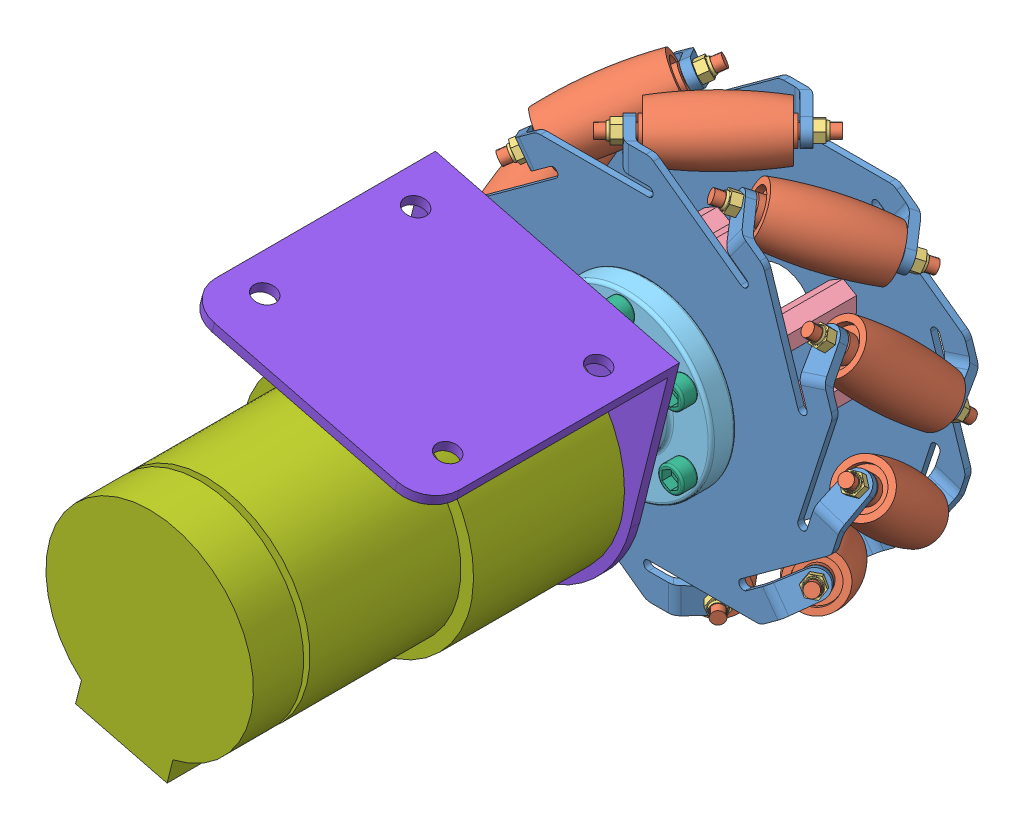
SolidWorks assembly 右前轮, configuration 默认. Lengths in mm.
Overall size (73.24 70.84 106.5).
61 component instances, 8 part files, 9 mates.
Components (placement in the parent):
- 麦克纳姆轮装配-1: 麦克纳姆轮装配 [默认] at (2.8929 6.1368 18.4053) size (73.24 68.83 28.84)
  - 麦克纳姆轮-1: 麦克纳姆轮 [默认] at (0.4661 -9.5096 64.9154) size (62.94 61.45 5.94)
  - 麦克纳姆轮-2: 麦克纳姆轮 [默认] at (0.4661 -9.5096 44.7758) x (-1 0 0) z (0 0 -1) size (62.94 61.45 5.94)
  - 辊子-3: 辊子 [默认] at (-10.8507 19.0898 66.1624) x (0.707107 0 -0.707107) z (0.707107 0 0.707107) size (28 9.23 9.23)
  - 辊子-4: 辊子 [默认] at (-25.5101 6.9683 66.1753) x (0.572061 0.415627 -0.707107) z (-0.42304 -0.589076 -0.688496) size (28 9.23 9.23)
  - 辊子-5: 辊子 [默认] at (-30.2306 -11.4349 66.1624) x (0.218508 0.672499 -0.707107) z (0.707107 0.390255 0.589662) size (28 9.23 9.23)
  - 辊子-6: 辊子 [默认] at (-23.2364 -29.1103 66.1624) x (-0.218508 0.672499 -0.707107) z (0.108472 0.736865 0.667281) size (28 9.23 9.23)
  - 辊子-7: 辊子 [默认] at (-25.5101 -25.9875 43.5158) x (0.572061 -0.415627 0.707107) z (-0.707107 0.186947 0.681946) size (28 9.23 9.23)
  - 辊子-8: 辊子 [默认] at (-10.8636 -38.109 43.5158) x (0.707107 0 0.707107) z (0.12537 -0.984157 -0.12537) size (28 9.23 9.23)
  - 辊子-9: 辊子 [默认] at (8.1104 -39.3064 43.5158) x (0.572061 0.415627 0.707107) z (-0.707107 -0.186947 0.681946) size (28 9.23 9.23)
  - 辊子-10: 辊子 [默认] at (24.1647 -29.1225 43.5158) x (0.218508 0.672499 0.707107) z (-0.707107 -0.390255 0.589662) size (28 9.23 9.23)
  - 辊子-11: 辊子 [默认] at (8.1209 20.2797 66.1624) x (0.572061 -0.415627 -0.707107) z (0.707107 -0.186947 0.681946) size (28 9.23 9.23)
  - 辊子-12: 辊子 [默认] at (31.1668 -11.4472 43.5158) x (-0.218508 0.672499 0.707107) z (-0.805898 -0.532961 0.25784) size (28 9.23 9.23)
  - M2【螺母】-1: M2【螺母】 [默认] at (-9.3907 18.6798 46.2506) x (0.808299 -0.139279 0.572061) z (-0.572061 -0.415627 0.707107) size (2.79 3.22 1.95)
  - M2【螺母】-2: M2【螺母】 [默认] at (9.0611 19.0898 46.2506) x (0.707107 0 0.707107) z (-0.707107 0 0.707107) size (2.79 3.22 1.95)
  - M2【螺母】-3: M2【螺母】 [默认] at (24.2299 8.5758 46.2506) x (0.808299 0.139279 0.572061) z (-0.572061 0.415627 0.707107) size (2.79 3.22 1.95)
  - M2【螺母】-4: M2【螺母】 [默认] at (30.3217 -8.8462 46.2506) x (0.972031 0.086079 0.218508) z (-0.218508 0.672499 0.707107) size (2.79 3.22 1.95)
  - M2【螺母】-5: M2【螺母】 [默认] at (25.0098 -26.5216 46.2506) x (0.972031 -0.086079 -0.218508) z (0.218508 0.672499 0.707107) size (2.79 3.22 1.95)
  - M2【螺母】-6: M2【螺母】 [默认] at (10.323 -37.699 46.2506) x (0.808299 -0.139279 -0.572061) z (0.572061 0.415627 0.707107) size (2.79 3.22 1.95)
  - M2【螺母】-7: M2【螺母】 [默认] at (-8.1288 -38.109 46.2506) x (0.707107 0 -0.707107) z (0.707107 0 0.707107) size (2.79 3.22 1.95)
  - M2【螺母】-8: M2【螺母】 [默认] at (-23.2976 -27.595 46.2506) x (0.808299 0.139279 -0.572061) z (0.572061 -0.415627 0.707107) size (2.79 3.22 1.95)
  - M2【螺母】-9: M2【螺母】 [默认] at (-29.3895 -10.173 46.2506) x (0.972031 0.086079 -0.218508) z (0.218508 -0.672499 0.707107) size (2.79 3.22 1.95)
  - M2【螺母】-10: M2【螺母】 [默认] at (-24.0775 7.5024 46.2506) x (0.972031 -0.086079 0.218508) z (-0.218508 -0.672499 0.707107) size (2.79 3.22 1.95)
  - M2【螺母】-11: M2【螺母】 [默认] at (30.3217 -10.173 63.4405) x (-0.703826 -0.39331 0.591554) z (-0.218508 -0.672499 -0.707107) size (2.79 3.22 1.95)
  - M2【螺母】-13: M2【螺母】 [默认] at (25.0098 7.5024 63.4405) x (0.835211 -0.245852 0.491913) z (0.218508 -0.672499 -0.707107) size (2.79 3.22 1.95)
  - M2【螺母】-14: M2【螺母】 [默认] at (10.323 18.6798 63.4405) x (0.731274 -0.131986 0.669192) z (0.572061 -0.415627 -0.707107) size (2.79 3.22 1.95)
  - M2【螺母】-15: M2【螺母】 [默认] at (-8.1288 19.0898 63.4405) x (0.610509 -0.504536 0.610509) z (0.707107 0 -0.707107) size (2.79 3.22 1.95)
  - M2【螺母】-16: M2【螺母】 [默认] at (-23.2976 8.5758 63.4405) x (0.785961 -0.524301 0.327679) z (0.572061 0.415627 -0.707107) size (2.79 3.22 1.95)
  - M2【螺母】-17: M2【螺母】 [默认] at (-29.3895 -8.8462 63.4405) x (0.874876 -0.455982 -0.163313) z (0.218508 0.672499 -0.707107) size (2.79 3.22 1.95)
  - M2【螺母】-18: M2【螺母】 [默认] at (-24.0775 -26.5216 63.4405) x (0.829372 -0.253837 -0.497703) z (-0.218508 0.672499 -0.707107) size (2.79 3.22 1.95)
  - M2【螺母】-19: M2【螺母】 [默认] at (-9.3907 -37.699 63.4405) x (0.565426 -0.424684 -0.707062) z (-0.572061 0.415627 -0.707107) size (2.79 3.22 1.95)
  - M2【螺母】-20: M2【螺母】 [默认] at (9.0611 -38.109 63.4405) x (0.556393 -0.617133 -0.556393) z (-0.707107 0 -0.707107) size (2.79 3.22 1.95)
  - M2【螺母】-21: M2【螺母】 [默认] at (24.2299 -27.595 63.4405) x (0.779137 -0.544759 -0.310134) z (-0.572061 -0.415627 -0.707107) size (2.79 3.22 1.95)
  - 20mm长-M3【六角铜柱】-1: 20mm长-M3【六角铜柱】 [默认] at (-9.4932 -3.7596 44.9154) size (4.27 4.93 20)
  - 20mm长-M3【六角铜柱】-2: 20mm长-M3【六角铜柱】 [默认] at (-9.4932 -15.2596 44.9154) x (0.5 0.866025 0) z (0 0 1) size (4.27 4.93 20)
  - 20mm长-M3【六角铜柱】-3: 20mm长-M3【六角铜柱】 [默认] at (0.4661 -21.0096 44.9154) x (-0.5 0.866025 0) z (0 0 1) size (4.27 4.93 20)
  - 20mm长-M3【六角铜柱】-4: 20mm长-M3【六角铜柱】 [默认] at (10.4254 -15.2596 44.9154) x (-1 0 0) z (0 0 1) size (4.27 4.93 20)
  - 20mm长-M3【六角铜柱】-5: 20mm长-M3【六角铜柱】 [默认] at (10.4254 -3.7596 44.9154) x (-0.5 -0.866025 0) z (0 0 1) size (4.27 4.93 20)
  - 20mm长-M3【六角铜柱】-6: 20mm长-M3【六角铜柱】 [默认] at (0.4661 1.9904 44.9154) x (0.5 -0.866025 0) z (0 0 1) size (4.27 4.93 20)
- 法兰联轴器-1: 法兰联轴器 [默认] at (3.3591 -3.3728 84.3207) size (28 28 16)
- M3-8【内六角螺丝】-1: M3-8【内六角螺丝】 [默认] at (3.3591 -14.8728 80.3207) size (4 4 10.5)
- M3-8【内六角螺丝】-2: M3-8【内六角螺丝】 [默认] at (13.3184 -9.1228 80.3207) x (0.5 0.866025 0) z (0 0 1) size (4 4 10.5)
- M3-8【内六角螺丝】-3: M3-8【内六角螺丝】 [默认] at (13.3184 2.3772 80.3207) x (-0.5 0.866025 0) z (0 0 1) size (4 4 10.5)
- M3-8【内六角螺丝】-4: M3-8【内六角螺丝】 [默认] at (3.3591 8.1272 80.3207) x (-1 0 0) z (0 0 1) size (4 4 10.5)
- M3-8【内六角螺丝】-5: M3-8【内六角螺丝】 [默认] at (-6.6002 2.3772 80.3207) x (-0.5 -0.866025 0) z (0 0 1) size (4 4 10.5)
- M3-8【内六角螺丝】-6: M3-8【内六角螺丝】 [默认] at (-6.6002 -9.1228 80.3207) x (0.5 -0.866025 0) z (0 0 1) size (4 4 10.5)
- M3-8【内六角螺丝】-7: M3-8【内六角螺丝】 [默认] at (3.3591 -14.8728 70.1811) x (1 0 0) z (0 0 -1) size (4 4 10.5)
- M3-8【内六角螺丝】-8: M3-8【内六角螺丝】 [默认] at (-6.6002 -9.1228 70.1811) x (0.5 -0.866025 0) z (0 0 -1) size (4 4 10.5)
- M3-8【内六角螺丝】-9: M3-8【内六角螺丝】 [默认] at (-6.6002 2.3772 70.1811) x (-0.5 -0.866025 0) z (0 0 -1) size (4 4 10.5)
- M3-8【内六角螺丝】-10: M3-8【内六角螺丝】 [默认] at (3.3591 8.1272 70.1811) x (-1 0 0) z (0 0 -1) size (4 4 10.5)
- M3-8【内六角螺丝】-11: M3-8【内六角螺丝】 [默认] at (13.3184 2.3772 70.1811) x (-0.5 0.866025 0) z (0 0 -1) size (4 4 10.5)
- M3-8【内六角螺丝】-12: M3-8【内六角螺丝】 [默认] at (13.3184 -9.1228 70.1811) x (0.5 0.866025 0) z (0 0 -1) size (4 4 10.5)
- 电机总装-1: 电机总装 [默认] at (86.3591 63.7866 -71.3943) x (0.969845 -0.243724 0) z (0 0 1) size (40 46 75)
  - 减速比1：10【码盘减速电机】-1: 减速比1：10【码盘减速电机】 [默认] at (-64.1287 -78.3632 203.7151) x (1 0 0) z (0 0 -1) size (37 37 75)
  - 电机支架-2: 电机支架 [默认] at (-64.1287 -78.3632 179.7151) x (1 0 0) z (0 0 -1) size (40 46 40)
  - M3-8【内六角螺丝】-13: M3-8【内六角螺丝】 [默认] at (-56.3787 -64.9398 186.2151) x (-1 0 0) z (0 0 -1) size (4 4 10.5)
  - M3-8【内六角螺丝】-14: M3-8【内六角螺丝】 [默认] at (-71.8787 -64.9398 186.2151) x (-0.5 -0.866025 0) z (0 0 -1) size (4 4 10.5)
  - M3-8【内六角螺丝】-15: M3-8【内六角螺丝】 [默认] at (-79.6287 -78.3632 186.2151) x (0.5 -0.866025 0) z (0 0 -1) size (4 4 10.5)
  - M3-8【内六角螺丝】-16: M3-8【内六角螺丝】 [默认] at (-71.8787 -91.7866 186.2151) x (1 0 0) z (0 0 -1) size (4 4 10.5)
  - M3-8【内六角螺丝】-17: M3-8【内六角螺丝】 [默认] at (-56.3787 -91.7866 186.2151) x (0.5 0.866025 0) z (0 0 -1) size (4 4 10.5)
  - M3-8【内六角螺丝】-18: M3-8【内六角螺丝】 [默认] at (-48.6287 -78.3632 186.2151) x (-0.5 0.866025 0) z (0 0 -1) size (4 4 10.5)
Mates (geometry in assembly coordinates):
- 同心1: concentric: cylinder of assembly; cylinder of assembly; cylinder of 麦克纳姆轮装配-1/麦克纳姆轮-1 through (3.3591 -3.3728 83.3207) axis (0 0 1) radius 5; cylinder of 法兰联轴器-1 through (3.3591 -3.3728 84.3207) axis (0 0 1) radius 3
- 同心2: concentric: cylinder of assembly; cylinder of assembly; cylinder of 麦克纳姆轮装配-1/麦克纳姆轮-1 through (3.3591 8.1272 83.3207) axis (0 0 1) radius 1.5; cylinder of 法兰联轴器-1 through (3.3591 8.1272 88.3207) axis (0 0 -1) radius 1.5
- 重合1: coincident: plane of assembly; plane of assembly; plane of 麦克纳姆轮装配-1/麦克纳姆轮-1 through (3.3591 22.3772 84.3207) normal (0 0 1); plane of 法兰联轴器-1 through (3.3591 -3.3728 84.3207) normal (0 0 -1)
- 同心3: concentric: cylinder of assembly; cylinder of assembly; cylinder of 法兰联轴器-1 through (3.3591 -14.8728 88.3207) axis (0 0 -1) radius 1.5; cylinder of M3-8【内六角螺丝】-1 through (3.3591 -14.8728 88.3207) axis (0 0 -1) radius 1.5
- 重合2: coincident: plane of assembly; plane of assembly; plane of 法兰联轴器-1 through (3.3591 -3.3728 88.3207) normal (0 0 1); plane of M3-8【内六角螺丝】-1 through (3.3591 -14.8728 88.3207) normal (0 0 -1)
- 同心4: concentric: cylinder of assembly; cylinder of assembly; cylinder of 麦克纳姆轮装配-1/麦克纳姆轮-2 through (3.3591 -14.8728 63.1811) axis (0 0 -1) radius 1.5; cylinder of M3-8【内六角螺丝】-7 through (3.3591 -14.8728 62.1811) axis (0 0 1) radius 1.5
- 重合3: coincident: plane of assembly; plane of assembly; plane of 麦克纳姆轮装配-1/麦克纳姆轮-2 through (3.3591 22.3772 62.1811) normal (0 0 -1); plane of M3-8【内六角螺丝】-7 through (3.3591 -14.8728 62.1811) normal (0 0 1)
- 同心5: concentric: cylinder of 法兰联轴器-1 through (3.3591 -3.3728 84.3207) axis (0 0 1) radius 3; cylinder of ? through (3.3591 -3.3728 101.3421) axis (0 0 1) radius 3
- 距离1: distance = 2 mm: plane of assembly; plane of assembly; plane of 法兰联轴器-1 through (3.3591 -3.3728 100.3207) normal (0 0 1); plane of 电机总装-1/减速比1：10【码盘减速电机】-1 through (3.3591 -3.3728 102.3207) normal (0 0 -1)
